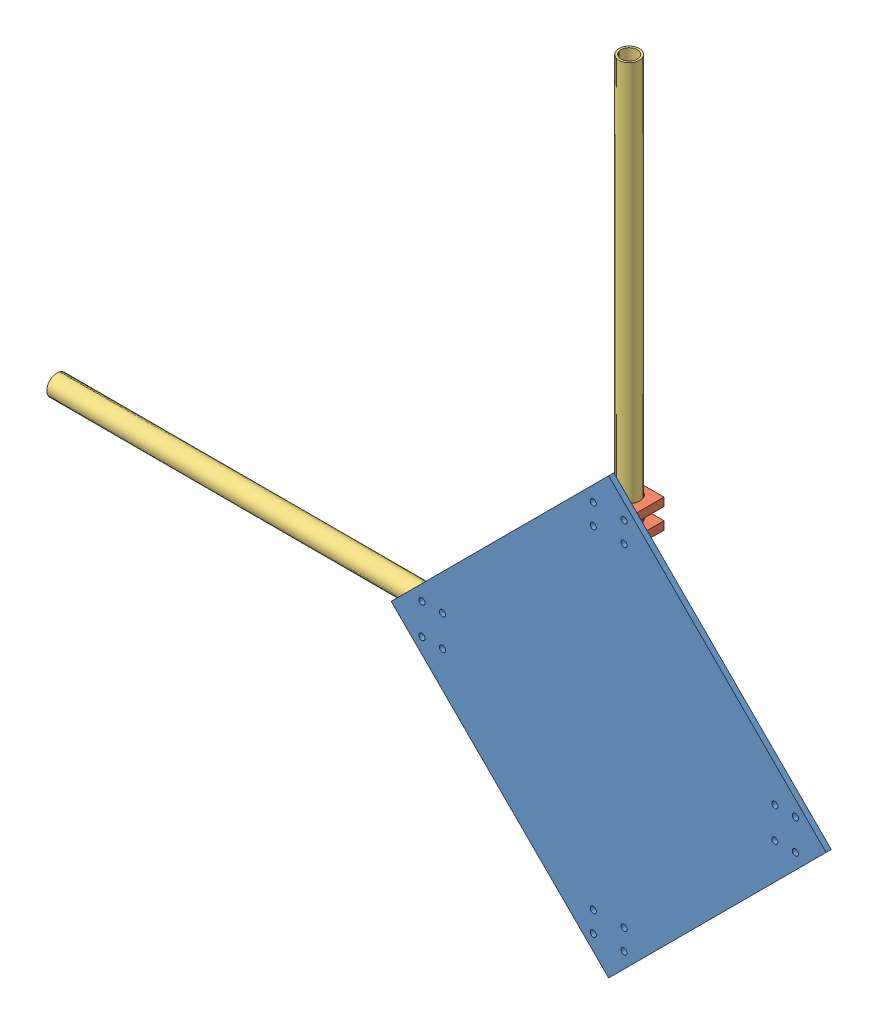
SolidWorks assembly Assem1, configuration Default. Lengths in mm.
Overall size (385.13 385.13 17.5).
9 component instances, 3 part files, 17 mates.
Components (placement in the parent):
- base-1: base [Default] at (47.9878 25.3697 163.9547) size (212.13 212.13 2.5)
- holder-1: holder [Default] at (38.4878 220.5018 163.9547) size (19 4 15)
- holder-2: holder [Default] at (57.4878 210.5018 148.9547) x (-1 0 0) z (0 0 -1) size (19 4 15)
- arm_tube1-1: arm_tube1 [Default] at (47.9878 210.5018 156.4547) x (0 1 0) z (0 0 1) size (200 10 10)
- holder-3: holder [Default] at (-41.0782 121.9358 163.9547) x (0 1 0) z (0 0 1) size (19 4 15)
- holder-4: holder [Default] at (-35.0782 140.9358 163.9547) x (0 -1 0) z (0 0 1) size (19 4 15)
- arm_tube1-2: arm_tube1 [Default] at (-231.0782 131.4358 156.4547) size (200 10 10)
- holder-5: holder [Default] at (38.4878 38.3697 163.9547) size (19 4 15)
- holder-6: holder [Default] at (38.4878 48.3697 163.9547) size (19 4 15)
Mates (geometry in assembly coordinates):
- Coincident1: coincident: circle of base-1; circle of holder-1
- Coincident2: coincident: circle of base-1; circle of holder-1
- Coincident3: coincident: circle of base-1; circle of holder-2
- Coincident4: coincident: circle of base-1; circle of holder-2
- Concentric5: concentric: cylinder of holder-2 through (47.9878 214.5018 156.4547) axis (0 -1 0) radius 5.25; cylinder of arm_tube1-1 through (47.9878 410.5018 156.4547) axis (0 -1 0) radius 5
- Coincident5: coincident: plane of holder-2 through (57.4878 210.5018 148.9547) normal (0 -1 0); plane of arm_tube1-1 through (47.9878 210.5018 156.4547) normal (0 -1 0)
- Concentric6: concentric: cylinder of base-1 through (-43.0782 138.9358 166.4547) axis (0 0 -1) radius 1.5; circle of holder-3
- Coincident7: coincident: circle of base-1; circle of holder-3
- Coincident8: coincident: circle of base-1; circle of holder-4
- Concentric7: concentric: circle of base-1; circle of holder-4
- Coincident12: coincident: circle of base-1; circle of holder-4
- Concentric8: concentric: cylinder of holder-4 through (-31.0782 131.4358 156.4547) axis (-1 0 0) radius 5.25; cylinder of arm_tube1-2 through (-31.0782 131.4358 156.4547) axis (-1 0 0) radius 5
- Coincident13: coincident: plane of holder-4 through (-31.0782 140.9358 163.9547) normal (1 0 0); plane of arm_tube1-2 through (-31.0782 131.4358 156.4547) normal (1 0 0)
- Coincident14: coincident: circle of base-1; circle of holder-5
- Coincident15: coincident: circle of base-1; circle of holder-5
- Coincident16: coincident: circle of base-1; circle of holder-6
- Coincident17: coincident: circle of base-1; circle of holder-6
